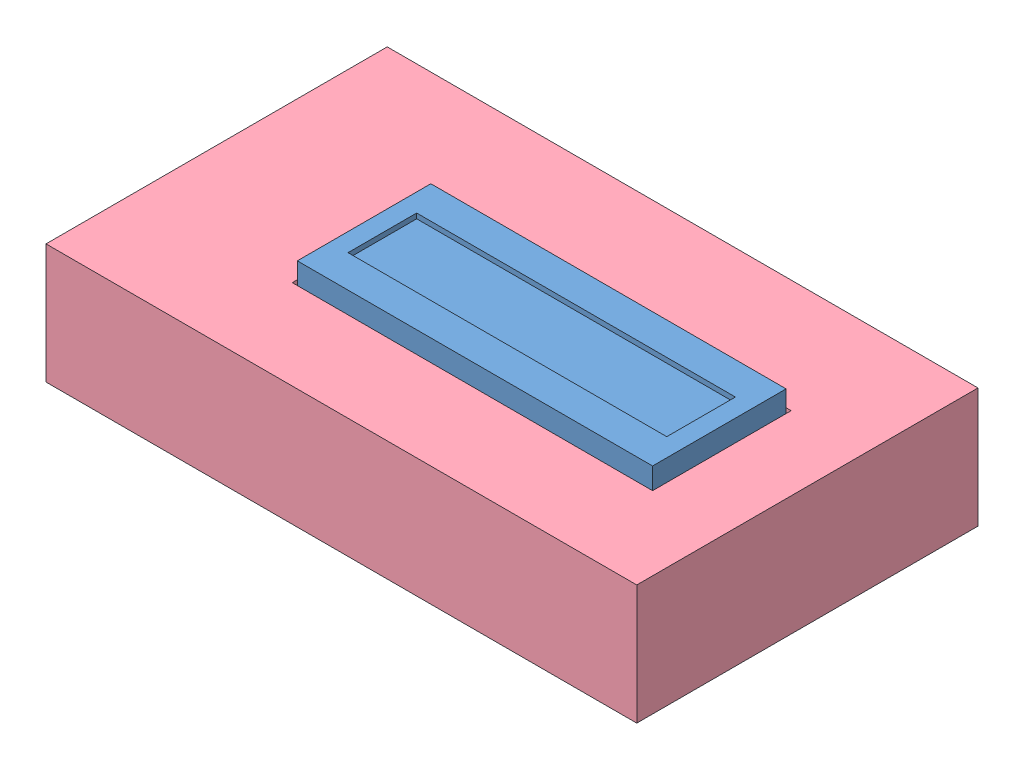
SolidWorks assembly Thermostat, configuration Default. Lengths in mm.
Overall size (119.11 27.94 68.8).
4 component instances, 4 part files, 7 mates.
Components (placement in the parent):
- ParallaxLCD-1: ParallaxLCD [Default] at (-43.17 4.5713 18.9194) size (80.01 25.17 36.07)
- Protoboard-1: Protoboard [Default] at (-63.4552 -9.9067 24.2911) size (75 1.02 51)
- TheThing-1: TheThing [Default] at (15.4339 -3.2449 -28.1359) x (0 0 1) z (0 1 0) size (55.37 25.95 5.88)
- CaseTop-1: CaseTop [Default] at (-43.17 6.1207 18.9194) x (1 0 0) z (0 1 0) size (119.11 68.8 24.13)
Mates (geometry in assembly coordinates):
- Coincident1: coincident anti-aligned: plane of ParallaxLCD-1 through (-43.17 -8.8907 18.9194) normal (0 -1 0); plane of Protoboard-1 through (-63.4552 -8.8907 24.2911) normal (0 1 0)
- Parallel1: parallel anti-aligned: plane of ParallaxLCD-1 through (-43.17 4.5713 18.9194) normal (0 -1 0); plane of TheThing-1 through (15.4339 -0.7049 -28.1359) normal (0 1 0)
- Parallel2: parallel anti-aligned: plane of ParallaxLCD-1 through (36.84 6.1207 18.9194) normal (1 0 0); plane of TheThing-1 through (15.4339 -0.7049 -28.1359) normal (-1 0 0)
- InPlace1: in place: plane of ParallaxLCD-1 through (-43.17 6.1207 18.9194) normal (0 1 0); plane of ? through (0 6.1207 0) normal (0 1 0); moOrthogonalPlaneRef_w of ParallaxLCD-1 through (-43.17 6.1207 18.9194) normal (0 1 0); plane of ? through (0 6.1207 0) normal (0 0 -1); plane of ParallaxLCD-1 through (-43.17 6.1207 18.9194) normal (0 1 0); line of ? through (-55 0 6.1207) axis (0 1 0); plane of ParallaxLCD-1 through (-43.17 6.1207 18.9194) normal (0 1 0); unknown of CaseTop-1
- Coincident2: coincident aligned: plane of ParallaxLCD-1; plane of CaseTop-1
- Coincident3: coincident aligned: moOrthogonalPlaneRef_w of ParallaxLCD-1 through (-43.17 6.1207 18.9194) normal (0 0 -1); plane of CaseTop-1 through (-43.17 6.1207 18.9194) normal (0 0 -1)
- Coincident4: coincident anti-aligned: moOrthogonalPlaneRef_w of ParallaxLCD-1 through (-43.17 6.1207 18.9194) normal (-1 0 0); plane of CaseTop-1
